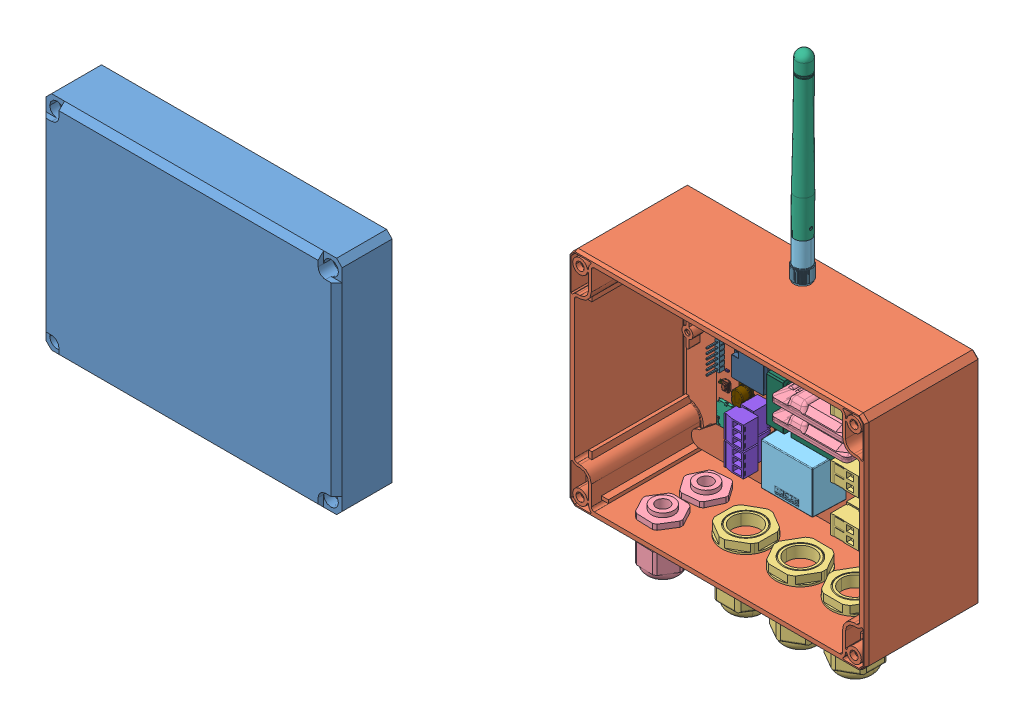
SolidWorks assembly Caixa com bucins e antena, configuration Default. Lengths in mm.
Overall size (347.73 263.98 160.3).
114 component instances, 24 part files, 8 mates.
Components (placement in the parent):
- DABP121609GE_1__3-1: DABP121609GE_1__3 [Default] at (-187.725 86.8367 159.2976) size (160 120 33)
- DABP121609GE_1__5-1: DABP121609GE_1__5 [Default] at (0 60 0) x (1 0 0) z (0 0 -1) size (160 120 62.5)
- Mesocosmo.step-3: Mesocosmo.step [Default] at (-104.4 -40.7 9.5) x (0 1 0) z (0 0 1) size (98.6 128.6 30.49)
  - __________________________2EDG-5.08-02P.step-1: __________________________2EDG-5.08-02P.step [Default] at (134.8 -136 1.65) x (1 0 0) z (0 -1 0) size (11.56 25.08 15.61)
    - COMPOUND-2.step-1: COMPOUND-2.step [Default] at origin size (11.56 25.08 15.61)
  - __________________________2EDG-5.08-02P.step-2: __________________________2EDG-5.08-02P.step [Default] at (103.1 -136 1.65) x (1 0 0) z (0 -1 0) size (11.56 25.08 15.61)
    - COMPOUND-2.step-1: COMPOUND-2.step [Default] at origin size (11.56 25.08 15.61)
  - __________________________2EDG-5.08-02P.step-3: __________________________2EDG-5.08-02P.step [Default] at (78.3 -136 1.65) x (1 0 0) z (0 -1 0) size (11.56 25.08 15.61)
    - COMPOUND-2.step-1: COMPOUND-2.step [Default] at origin size (11.56 25.08 15.61)
  - Crydom_-_CX240D5R.step-1: Crydom_-_CX240D5R.step [Default] at (110.3 -142.1 1.65) x (0 -1 0) z (-1 0 0) size (41.67 30.49 6.87)
    - COMPOUND.step-1: COMPOUND.step [Default] at origin size (41.67 30.49 6.87)
  - Crydom_-_CX240D5R.step-2: Crydom_-_CX240D5R.step [Default] at (119.3 -142.1 1.65) x (0 -1 0) z (-1 0 0) size (41.67 30.49 6.87)
    - COMPOUND.step-1: COMPOUND.step [Default] at origin size (41.67 30.49 6.87)
  - RAC03-05SK.step-1: RAC03-05SK.step [Default] at (78.8 -109.6 1.65) x (1 0 0) z (0 -1 0) size (23.5 22.9 28.5)
    - COMPOUND-0.step-1: COMPOUND-0.step [Default] at origin size (23.5 22.9 28.5)
  - microSD_HC_Hirose_DM3D-SF.step-1: microSD_HC_Hirose_DM3D-SF.step [Default] at (74.9 -61 1.65) size (11.96 11.46 1.56)
    - SOLID.step-1: SOLID.step [Default] at origin size (11.96 11.46 1.56)
  - P2300SDLRP.step-1: P2300SDLRP.step [Default] at (78.9 -133.5 1.65) size (5.6 3.63 2.75)
    - COMPOUND-1.step-1: COMPOUND-1.step [Default] at origin size (5.6 3.63 2.75)
  - __________________________15EDG-3.81-3.step-1: __________________________15EDG-3.81-3.step [Default] at (71.4 -79.5 1.65) size (12.25 11.03 21.75)
    - COMPOUND-3.step-1: COMPOUND-3.step [Default] at origin size (12.25 11.03 21.75)
  - __________________________15EDG-3.81-3.step-2: __________________________15EDG-3.81-3.step [Default] at (84.4 -79.5 1.65) size (12.25 11.03 21.75)
    - COMPOUND-3.step-1: COMPOUND-3.step [Default] at origin size (12.25 11.03 21.75)
  - SOIC-16_7.5x10.3mm_Pitch1.27mm.step-1: SOIC-16_7.5x10.3mm_Pitch1.27mm.step [Default] at (122.4 -77 1.65) x (0 -1 0) z (0 0 1) size (10.3 10.3 1.75)
    - SOLID-4.step-1: SOLID-4.step [Default] at origin size (10.3 10.3 1.75)
  - ESP32-WROOM-32U--3DModel-STEP-56544.step-1: ESP32-WROOM-32U--3DModel-STEP-56544.step [Default] at (104.4 -74 1.65) x (1 0 0) z (0 -1 0) size (18 3.3 19.2)
    - COMPOUND-5.step-1: COMPOUND-5.step [Default] at origin size (18 3.3 19.2)
  - EVQP2002W.step-1: EVQP2002W.step [Default] at (131.9 -86.5 1.65) x (0 -1 0) z (0 0 1) size (5.5 3.5 2.5)
    - SOLID-6.step-1: SOLID-6.step [Default] at origin size (5.5 3.5 2.5)
  - EVQP2002W.step-2: EVQP2002W.step [Default] at (131.9 -73 1.65) x (0 -1 0) z (0 0 1) size (5.5 3.5 2.5)
    - SOLID-6.step-1: SOLID-6.step [Default] at origin size (5.5 3.5 2.5)
  - EVQP2002W.step-3: EVQP2002W.step [Default] at (88.8 -59.9 1.65) x (-1 0 0) z (0 0 1) size (5.5 3.5 2.5)
    - SOLID-6.step-1: SOLID-6.step [Default] at origin size (5.5 3.5 2.5)
  - R_0603.step-1: R_0603.step [Default] at (112.4 -89.5 1.65) size (1.55 0.85 0.45)
    - SOLID-7.step-1: SOLID-7.step [Default] at origin size (1.55 0.85 0.45)
  - R_0603.step-2: R_0603.step [Default] at (121.4 -88 1.65) x (0 -1 0) z (0 0 1) size (1.55 0.85 0.45)
    - SOLID-7.step-1: SOLID-7.step [Default] at origin size (1.55 0.85 0.45)
  - R_0603.step-3: R_0603.step [Default] at (117.4 -85 1.65) x (-1 0 0) z (0 0 1) size (1.55 0.85 0.45)
    - SOLID-7.step-1: SOLID-7.step [Default] at origin size (1.55 0.85 0.45)
  - R_0603.step-4: R_0603.step [Default] at (90.4 -89.5 1.65) x (-1 0 0) z (0 0 1) size (1.55 0.85 0.45)
    - SOLID-7.step-1: SOLID-7.step [Default] at origin size (1.55 0.85 0.45)
  - R_0603.step-5: R_0603.step [Default] at (94.4 -88.5 1.65) x (0 -1 0) z (0 0 1) size (1.55 0.85 0.45)
    - SOLID-7.step-1: SOLID-7.step [Default] at origin size (1.55 0.85 0.45)
  - R_0603.step-6: R_0603.step [Default] at (95.4 -85.5 1.65) size (1.55 0.85 0.45)
    - SOLID-7.step-1: SOLID-7.step [Default] at origin size (1.55 0.85 0.45)
  - R_0603.step-7: R_0603.step [Default] at (124.4 -85.5 1.65) x (0 1 0) z (0 0 1) size (1.55 0.85 0.45)
    - SOLID-7.step-1: SOLID-7.step [Default] at origin size (1.55 0.85 0.45)
  - R_0603.step-8: R_0603.step [Default] at (126.9 -85.5 1.65) x (0 1 0) z (0 0 1) size (1.55 0.85 0.45)
    - SOLID-7.step-1: SOLID-7.step [Default] at origin size (1.55 0.85 0.45)
  - R_0603.step-9: R_0603.step [Default] at (75.4 -74 1.65) size (1.55 0.85 0.45)
    - SOLID-7.step-1: SOLID-7.step [Default] at origin size (1.55 0.85 0.45)
  - R_0603.step-10: R_0603.step [Default] at (88.4 -74.5 1.65) size (1.55 0.85 0.45)
    - SOLID-7.step-1: SOLID-7.step [Default] at origin size (1.55 0.85 0.45)
  - R_0603.step-11: R_0603.step [Default] at (110.2334 -86.5 1.65) x (0 1 0) z (0 0 1) size (1.55 0.85 0.45)
    - SOLID-7.step-1: SOLID-7.step [Default] at origin size (1.55 0.85 0.45)
  - R_0603.step-12: R_0603.step [Default] at (89.9 -66.5 1.65) x (0 1 0) z (0 0 1) size (1.55 0.85 0.45)
    - SOLID-7.step-1: SOLID-7.step [Default] at origin size (1.55 0.85 0.45)
  - R_0603.step-13: R_0603.step [Default] at (83.4 -66.5 1.65) x (0 -1 0) z (0 0 1) size (1.55 0.85 0.45)
    - SOLID-7.step-1: SOLID-7.step [Default] at origin size (1.55 0.85 0.45)
  - R_0603.step-14: R_0603.step [Default] at (133.4044 -92.3234 1.65) x (0 -1 0) z (0 0 1) size (1.55 0.85 0.45)
    - SOLID-7.step-1: SOLID-7.step [Default] at origin size (1.55 0.85 0.45)
  - R_0603.step-15: R_0603.step [Default] at (130.9 -79 1.65) x (0 -1 0) z (0 0 1) size (1.55 0.85 0.45)
    - SOLID-7.step-1: SOLID-7.step [Default] at origin size (1.55 0.85 0.45)
  - SOT-23.step-1: SOT-23.step [Default] at (117.9 -88.5 1.65) x (0 -1 0) z (0 0 1) size (2.35 2.9 1)
    - SOLID-8.step-1: SOLID-8.step [Default] at origin size (2.35 2.9 1)
  - SOT-23.step-2: SOT-23.step [Default] at (91.4 -86.5 1.65) x (0 -1 0) z (0 0 1) size (2.35 2.9 1)
    - SOLID-8.step-1: SOLID-8.step [Default] at origin size (2.35 2.9 1)
  - PinHeader_1x06_P2.54mm_Vertical.step-1: PinHeader_1x06_P2.54mm_Vertical.step [Default] at (108.5 -56.7 1.65) x (0 -1 0) z (0 0 1) size (2.54 15.24 11.54)
    - SOLID-9.step-1: SOLID-9.step [Default] at origin size (2.54 15.24 11.54)
  - Fuse_Holders_SMD_5x20mm_+_Fuse_+_cap.step-1: Fuse_Holders_SMD_5x20mm_+_Fuse_+_cap.step [Default] at (98.9 -119 1.65) x (-1 0 0) z (0 1 0) size (9.6 13.28 24.89)
    - COMPOUND-10.step-1: COMPOUND-10.step [Default] at origin size (9.6 13.28 24.89)
  - Fuse_Holders_SMD_5x20mm_+_Fuse_+_cap.step-2: Fuse_Holders_SMD_5x20mm_+_Fuse_+_cap.step [Default] at (128.4 -119 1.65) x (1 0 0) z (0 -1 0) size (9.6 13.28 24.89)
    - COMPOUND-10.step-1: COMPOUND-10.step [Default] at origin size (9.6 13.28 24.89)
  - Fuse_Holders_SMD_5x20mm_+_Fuse_+_cap.step-3: Fuse_Holders_SMD_5x20mm_+_Fuse_+_cap.step [Default] at (105.9 -98.5 1.65) x (0 1 0) z (1 0 0) size (9.6 13.28 24.89)
    - COMPOUND-10.step-1: COMPOUND-10.step [Default] at origin size (9.6 13.28 24.89)
  - led_0603.step-1: led_0603.step [Default] at (106.9 -89 1.65) size (1.6 0.8 1.1)
    - SOLID-11.step-1: SOLID-11.step [Default] at origin size (1.6 0.8 1.1)
  - led_0603.step-2: led_0603.step [Default] at (99.4 -89 1.65) size (1.6 0.8 1.1)
    - SOLID-11.step-1: SOLID-11.step [Default] at origin size (1.6 0.8 1.1)
  - led_0603.step-3: led_0603.step [Default] at (88.8 -56.4 1.65) x (-1 0 0) z (0 0 1) size (1.6 0.8 1.1)
    - SOLID-11.step-1: SOLID-11.step [Default] at origin size (1.6 0.8 1.1)
  - C_0603_1608Metric.step-1: C_0603_1608Metric.step [Default] at (126.4 -69.5 1.65) x (-1 0 0) z (0 0 1) size (1.6 0.8 0.8)
    - SOLID-12.step-1: SOLID-12.step [Default] at origin size (1.6 0.8 0.8)
  - C_0603_1608Metric.step-2: C_0603_1608Metric.step [Default] at (82.4 -74.5 1.65) x (0 -1 0) z (0 0 1) size (1.6 0.8 0.8)
    - SOLID-12.step-1: SOLID-12.step [Default] at origin size (1.6 0.8 0.8)
  - C_0603_1608Metric.step-3: C_0603_1608Metric.step [Default] at (80.4 -74.5 1.65) x (0 1 0) z (0 0 1) size (1.6 0.8 0.8)
    - SOLID-12.step-1: SOLID-12.step [Default] at origin size (1.6 0.8 0.8)
  - C_0603_1608Metric.step-4: C_0603_1608Metric.step [Default] at (85.9 -66.5 1.65) x (0 1 0) z (0 0 1) size (1.6 0.8 0.8)
    - SOLID-12.step-1: SOLID-12.step [Default] at origin size (1.6 0.8 0.8)
  - C_0603.step-1: C_0603.step [Default] at (88.9 -70.5 1.65) x (0 1 0) z (0 0 1) size (8.61 8.6 5.8)
    - SOLID-13.step-1: SOLID-13.step [Default] at origin size (8.61 8.6 5.8)
  - C_0603.step-2: C_0603.step [Default] at (91.4 -70.5 1.65) x (0 1 0) z (0 0 1) size (8.61 8.6 5.8)
    - SOLID-13.step-1: SOLID-13.step [Default] at origin size (8.61 8.6 5.8)
  - C_0603_1608Metric.step-5: C_0603_1608Metric.step [Default] at (71.4 -89 1.65) x (-1 0 0) z (0 0 1) size (1.6 0.8 0.8)
    - SOLID-12.step-1: SOLID-12.step [Default] at origin size (1.6 0.8 0.8)
  - CP_Elec_6.3x5.8.step-1: CP_Elec_6.3x5.8.step [Default] at (79.9 -89.5 1.65) size (8.61 8.6 5.8)
    - SOLID-13.step-1: SOLID-13.step [Default] at origin size (8.61 8.6 5.8)
  - C_0603_1608Metric.step-6: C_0603_1608Metric.step [Default] at (130.9044 -92.3234 1.65) x (0 -1 0) z (0 0 1) size (1.6 0.8 0.8)
    - SOLID-12.step-1: SOLID-12.step [Default] at origin size (1.6 0.8 0.8)
  - C_0603_1608Metric.step-7: C_0603_1608Metric.step [Default] at (95.7 -59.9 1.65) x (0 1 0) z (0 0 1) size (1.6 0.8 0.8)
    - SOLID-12.step-1: SOLID-12.step [Default] at origin size (1.6 0.8 0.8)
  - C_0603_1608Metric.step-8: C_0603_1608Metric.step [Default] at (133.4 -79 1.65) x (0 -1 0) z (0 0 1) size (1.6 0.8 0.8)
    - SOLID-12.step-1: SOLID-12.step [Default] at origin size (1.6 0.8 0.8)
  - BatteryHolder_Keystone_3000_1x12mm.step-1: BatteryHolder_Keystone_3000_1x12mm.step [Default] at (126.15 -60.75 1.65) x (-1 0 0) z (0 0 1) size (18.92 12.01 3.28)
    - COMPOUND-14.step-1: COMPOUND-14.step [Default] at origin size (18.92 12.01 3.28)
  - COMPOUND-16.step-1: COMPOUND-16.step [Default] at origin size (98.6 128.6 1.6)
- PE_PG11.step-1: PE_PG11.step [Default] at (-13.494 -29.7 32.3631) x (0.864804 0 0.50211) z (0 1 0) size (26 26 38.7)
- PE_PG11.step-2: PE_PG11.step [Default] at (16.3451 -29.7 32.7962) x (1 0 0) z (0 1 0) size (26 26 38.7)
- PE_PG11.step-3: PE_PG11.step [Default] at (44.9408 -29.7 31.7789) x (1 0 0) z (0 1 0) size (26 26 38.7)
- PG7.step-1: PG7.step [Default] at (-45.3762 0 21.9665) x (0.817032 0 -0.576593) z (0 1 0) size (19 21 31)
- PG7.step-2: PG7.step [Default] at (-46.4703 0 44.3187) x (0.882606 0 -0.470113) z (0 1 0) size (19 21 31)
- 2.4 GHz Antenna.STEP-1: 2.4 GHz Antenna.STEP [Default] at (8.9251 169.5143 22.3523) x (1 0 0) z (0 -0.999962 0.008727) size (10 9.99 107.5)
  - 2.4 GHz Antenna Base.STEP-1: 2.4 GHz Antenna Base.STEP [Default] at (-3.953 -2.3775 34.75) size (10 9.99 28.5)
  - 2.4 GHz Antenna Top.STEP-1: 2.4 GHz Antenna Top.STEP [Default] at (-3.953 -2.3775 1.75) size (9.01 9.28 86.5)
Mates (geometry in assembly coordinates):
- Coincident1: coincident anti-aligned: plane of DABP121609GE_1__5-1 through (77 0 61.5) normal (0 -1 0); plane of PE_PG11.step-3 through (44.9408 0 19.2215) normal (0 1 0)
- Coincident2: coincident anti-aligned: plane of DABP121609GE_1__5-1 through (77 0 61.5) normal (0 -1 0); plane of PE_PG11.step-2 through (16.3451 0 20.2388) normal (0 1 0)
- Coincident3: coincident anti-aligned: plane of DABP121609GE_1__5-1 through (77 0 61.5) normal (0 -1 0); plane of PE_PG11.step-1 through (-7.1888 0 21.5034) normal (0 1 0)
- Coincident5: coincident anti-aligned: plane of DABP121609GE_1__5-1 through (77 0 61.5) normal (0 -1 0); plane of PG7.step-1 through (-48.8358 0 17.0644) normal (0 1 0)
- Coincident6: coincident anti-aligned: plane of DABP121609GE_1__5-1 through (77 0 61.5) normal (0 -1 0); plane of PG7.step-2 through (-49.291 0 39.0231) normal (0 1 0)
- Coincident8: coincident anti-aligned: plane of DABP121609GE_1__5-1 through (60 15 9.5) normal (0 0 1); plane of Mesocosmo.step-3/COMPOUND-16.step-1 through (0.4403 60.0417 9.5) normal (0 0 -1)
- Concentric1: concentric anti-aligned: circle of DABP121609GE_1__5-1; circle of Mesocosmo.step-3/COMPOUND-16.step-1
- Concentric2: concentric anti-aligned: circle of DABP121609GE_1__5-1; circle of Mesocosmo.step-3/COMPOUND-16.step-1
